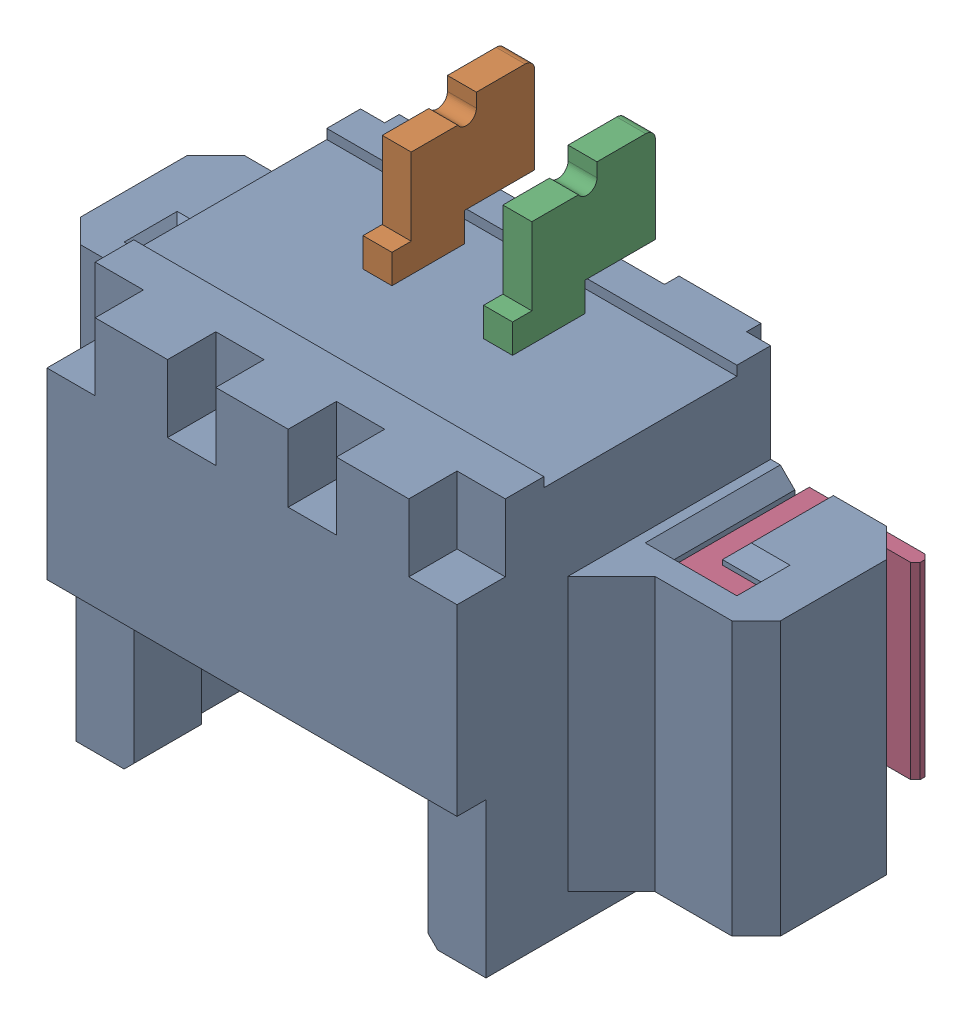
SolidWorks assembly 653102131822, configuration Default. Lengths in mm.
Overall size (7.25 5.4 3.41).
5 component instances, 3 part files, 0 mates.
Components (placement in the parent):
- 653102131822-1: 653102131822 [Default] at origin size (7.25 4.2 3.4)
- 6531xx131822_PIN-1: 6531xx131822_PIN [Default] at (-0.625 2.7 -0.425) x (1 0 0) z (0 -1 0) size (0.3 1.48 4.54)
- 6531xx131822_PIN-2: 6531xx131822_PIN [Default] at (0.625 2.7 -0.425) x (1 0 0) z (0 -1 0) size (0.3 1.48 4.54)
- 6531xx131822_PIN_FLANGE-1: 6531xx131822_PIN_FLANGE [Default] at (2.5 -0.095 -1.05) size (1.25 1.95 1.4)
- 6531xx131822_PIN_FLANGE-2: 6531xx131822_PIN_FLANGE [Default] at (-2.5 -0.095 -1.05) x (-1 0 0) z (0 0 1) size (1.25 1.95 1.4)
